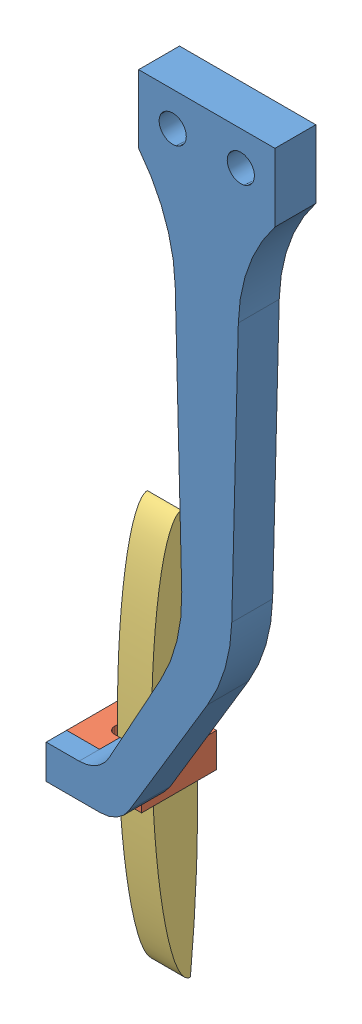
SolidWorks assembly Right Wiper, configuration Default. Lengths in mm.
Overall size (33.56 124.78 14.78).
3 component instances, 3 part files, 3 mates.
Components (placement in the parent):
- WiperArm-1: WiperArm [Default] at (38.4948 89.1909 60.5048) x (-1 0 0) z (0 0 -1) size (33.56 97.23 6)
- Hinge-2: Hinge [Default] at (20.4334 -3.0399 52.0048) size (11 5 11)
- Wiper Blade-2: Wiper Blade [Default] at (17.9334 29.5079 48.6667) x (1 0 0) z (0 -0.022041 0.999757) size (5 60 6.62)
Mates (geometry in assembly coordinates):
- Coincident1: coincident: circle of Hinge-2; circle of Wiper Blade-2
- Coincident2: coincident: line of WiperArm-1 through (14.9334 -3.0399 54.5048) axis (0 0 1); line of Hinge-2 through (14.9334 -3.0399 57.5048) axis (0 0 -1)
- Coincident4: coincident: line of WiperArm-1 through (22.8286 -3.0399 54.5048) axis (-1 0 0); line of Hinge-2 through (18.9334 -3.0399 54.5048) axis (1 0 0)
